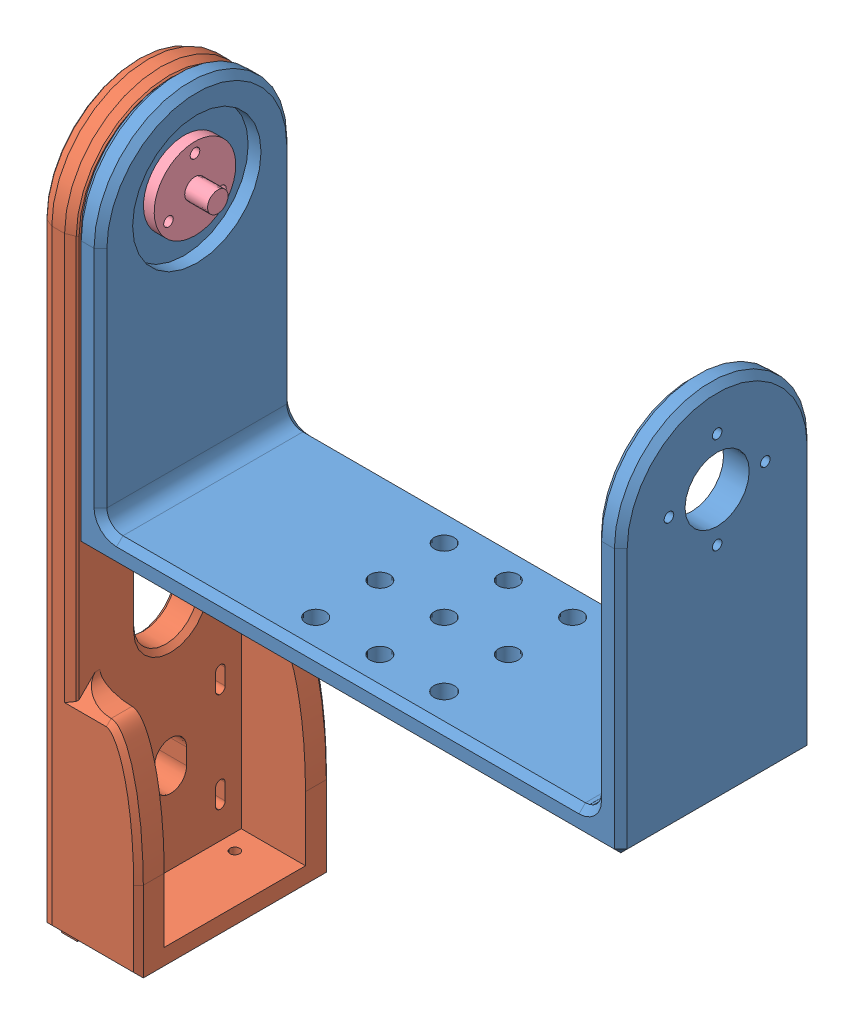
SolidWorks assembly rotary_sma_tilt, configuration Default. Lengths in mm.
Overall size (189.65 226.01 60.52).
5 component instances, 5 part files, 0 mates.
Components (placement in the parent):
- DUT_Bridge_rotarySMA-1: DUT_Bridge_rotarySMA [Default] at origin size (171.5 113 60)
- side_support_rotary_sma-1: side_support_rotary_sma [Default] at (-80.5865 -103.0069 -0.4201) x (-1 0 0) z (0 0 -1) size (30.1 225 60.2)
- rotary_sma_big_bearing-1: rotary_sma_big_bearing [Default] at (-92.7082 85.131 -0.3048) x (0 0 -1) z (1 0 0) size (40 40 6)
- Rotary_SMA-1: Rotary_SMA [Default] at (-80.7366 84.9957 0.1667) x (0 1 0) z (1 0 0) size (25.4 25.4 34.35)
- rotary_sma_bearing_flange-1: rotary_sma_bearing_flange [Default] at (-86.7468 84.7785 0.0139) x (0 0 1) z (-1 0 0) size (30 30 8)
